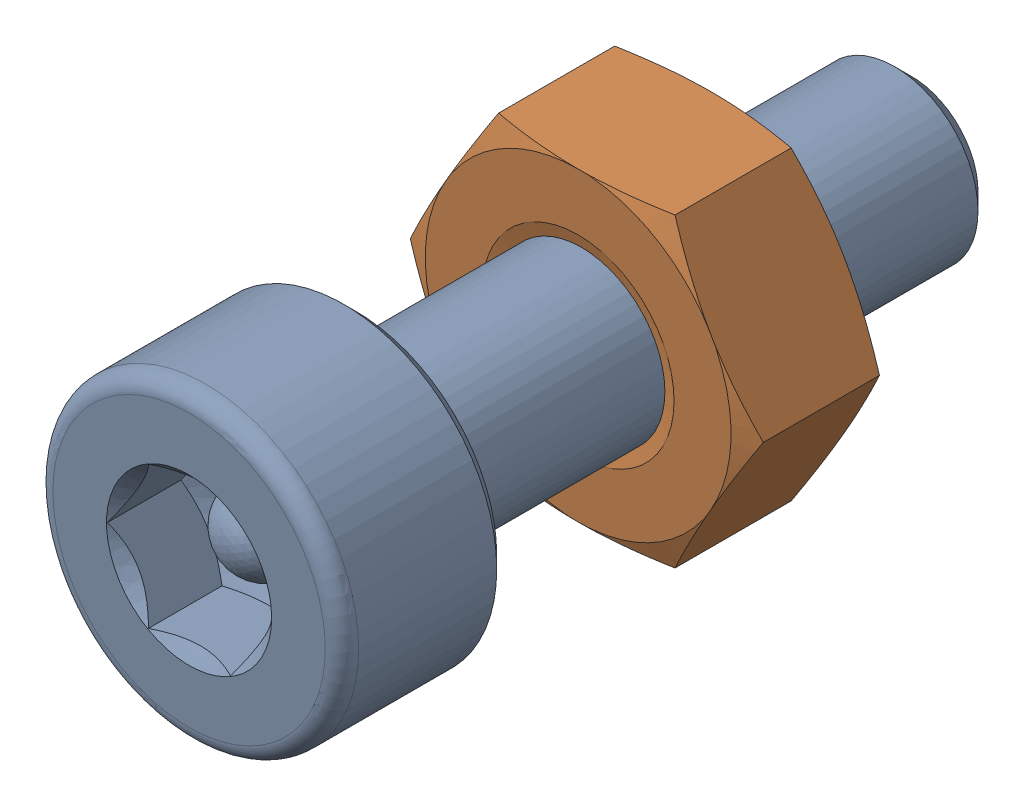
SolidWorks assembly Screw and Nut M3x010_011, configuration Varsayılan. Lengths in mm.
Overall size (6.35 5.5 13.14).
2 component instances, 2 part files, 0 mates.
Components (placement in the parent):
- M3x10-Screw010-1: M3x10-Screw010 [Varsayılan] at origin size (5.5 5.5 13.14)
- M3-Nut042-1: M3-Nut042 [Varsayılan] at (0 0 -4) x (-1 0 0) z (0 0 -1) size (6.35 5.5 2.4)
